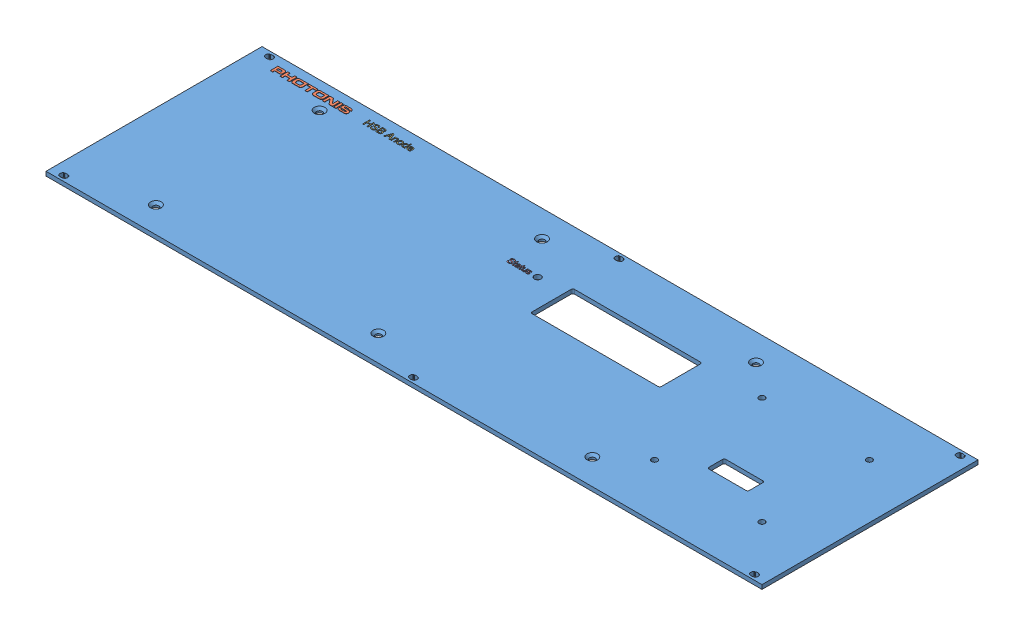
SolidWorks assembly MLA-0387-M10, configuration Default. Lengths in mm.
Overall size (426.52 2.65 128.7).
4 component instances, 4 part files, 9 mates.
Components (placement in the parent):
- MLA-0387-M1-1: MLA-0387-M1 [Default] at (-7.8975 -174.6729 597.0963) size (426.52 2.5 128.7)
- LOGO PHOTONIS-1: LOGO PHOTONIS [Default] at (9.7425 205.5771 259.7963) x (1 0 0) z (0 1 0) size (45.16 4.45 0.15)
- Anode text-1: Anode text [Default] at (64.2855 205.4271 259.8791) size (28.26 0.1 4.1)
- Status text-1: Status text [Default] at (178.1079 205.4271 288.0463) size (13.33 0.1 3.59)
Mates (geometry in assembly coordinates):
- Coincident1: coincident anti-aligned: plane of MLA-0387-M1-1 through (0.1829 205.4271 294.0204) normal (0 1 0); plane of LOGO PHOTONIS-1 through (13.9262 205.4271 256.4739) normal (0 -1 0)
- Distance1: distance = 15 mm aligned: plane of LOGO PHOTONIS-1 through (9.7425 205.4271 259.7963) normal (-1 0 0); plane of MLA-0387-M1-1 through (-5.2575 202.9271 334.0463) normal (-1 0 0)
- Distance2: distance = 10 mm anti-aligned: plane of LOGO PHOTONIS-1 through (11.1035 205.4271 259.7963) normal (0 0 1); plane of MLA-0387-M1-1 through (-5.2575 202.9271 249.7963) normal (0 0 -1)
- Coincident4: coincident anti-aligned: plane of MLA-0387-M1-1 through (0.1829 205.4271 294.0204) normal (0 1 0); plane of Anode text-1 through (64.2855 205.4271 259.8791) normal (0 -1 0)
- Distance3: distance = 10 mm anti-aligned: plane of Anode text-1 through (65.3066 205.5271 259.7963) normal (0 0 1); plane of MLA-0387-M1-1 through (-5.2575 202.9271 249.7963) normal (0 0 -1)
- Distance4: distance = 70 mm aligned: plane of Anode text-1 through (64.7425 205.5271 259.7963) normal (-1 0 0); plane of MLA-0387-M1-1 through (-5.2575 202.9271 334.0463) normal (-1 0 0)
- Coincident7: coincident anti-aligned: plane of MLA-0387-M1-1 through (0.1829 205.4271 294.0204) normal (0 1 0); plane of Status text-1 through (178.7733 205.4271 287.7934) normal (0 -1 0)
- Distance5: distance = 38.25 mm anti-aligned: plane of Status text-1 through (189.1015 205.5271 288.0463) normal (0 0 1); plane of MLA-0387-M1-1 through (-5.2575 202.9271 249.7963) normal (0 0 -1)
- Distance6: distance = 187 mm: plane of Status text-1 through (181.7425 205.5271 287.3277) normal (-1 0 0); line of MLA-0387-M1-1 through (-5.2575 205.4271 378.4963) axis (0 0 -1)
